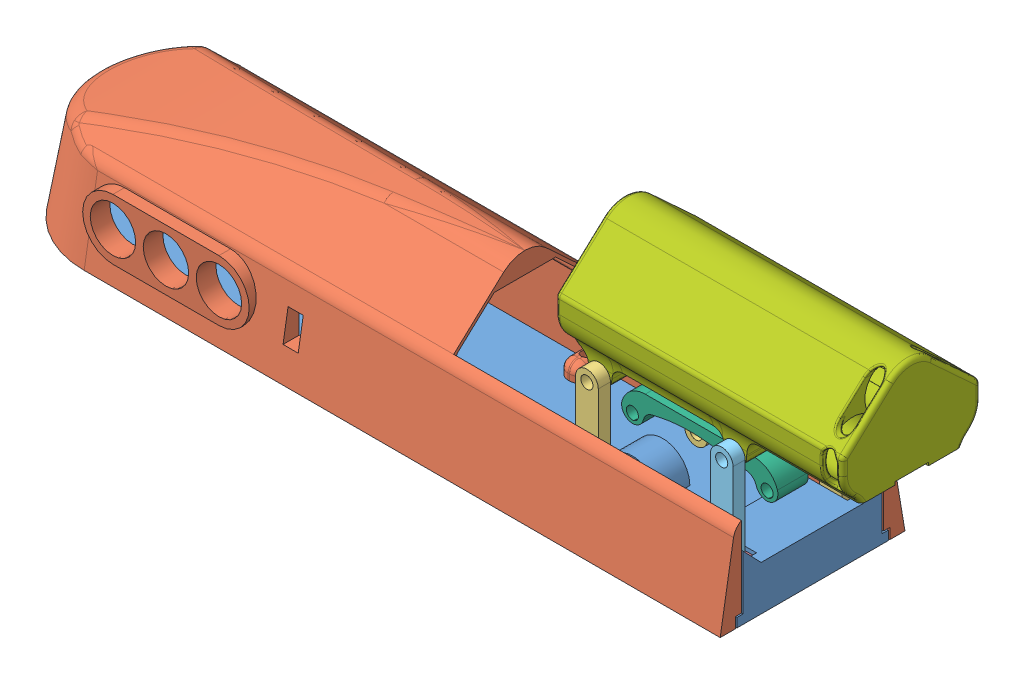
SolidWorks assembly Wrist Rockets Assembly, configuration Default. Lengths in mm.
Overall size (273.36 80.52 61).
9 component instances, 7 part files, 24 mates.
Components (placement in the parent):
- EC Base Plate-1: EC Base Plate [Default] at (1.705 116.0964 230.214) size (235 21 50)
- Casing-1: Casing [Default] at (211.705 119.0964 230.214) size (240.5 48 61)
- Lifter Bar-1: Lifter Bar [Default] at (157.205 156.5964 221.214) x (0 -1 0) z (-1 0 0) size (40 4 7.5)
- N20 Gear Motor-1: N20 Gear Motor [Default] at (207.705 119.0964 218.214) x (0 0 -1) z (1 0 0) size (31 10 12)
- Lifter Bar w Key-1: Lifter Bar w Key [Default] at (201.705 156.5964 221.214) x (0 -1 0) z (-1 0 0) size (40 4 7.5)
- Lifter Bar-2: Lifter Bar [Default] at (201.705 156.5964 185.214) x (0 -1 0) z (-1 0 0) size (40 4 7.5)
- Lifter Bar-3: Lifter Bar [Default] at (157.205 156.5964 185.214) x (0 -1 0) z (-1 0 0) size (40 4 7.5)
- Lifter Connector-1: Lifter Connector [Default] at (160.955 137.3464 205.214) size (51.62 10.5 10)
- Rocket Tube Housing-1: Rocket Tube Housing [Default] at (160.955 153.5964 210.714) size (95.11 43.02 45.5)
Mates (geometry in assembly coordinates):
- Coincident1: coincident aligned: plane of EC Base Plate-1 through (1.705 119.0964 230.214) normal (0 0 1); plane of Casing-1 through (211.705 119.0964 230.214) normal (0 0 1)
- Coincident2: coincident aligned: plane of EC Base Plate-1 through (1.705 119.0964 205.214) normal (0 1 0); plane of Casing-1 through (211.705 119.0964 230.214) normal (0 1 0)
- Coincident3: coincident aligned: plane of EC Base Plate-1 through (211.705 119.0964 230.214) normal (1 0 0); plane of Casing-1 through (211.705 119.0964 230.214) normal (1 0 0)
- Coincident4: coincident anti-aligned: plane of EC Base Plate-1 through (1.705 119.0964 205.214) normal (0 1 0); plane of N20 Gear Motor-1 through (207.705 119.0964 218.214) normal (0 -1 0)
- Distance1: distance = 4 mm aligned: plane of N20 Gear Motor-1 through (207.705 129.0964 218.214) normal (1 0 0); plane of EC Base Plate-1 through (211.705 119.0964 230.214) normal (1 0 0)
- Distance2: distance = 12 mm aligned: plane of N20 Gear Motor-1 through (207.705 129.0964 218.214) normal (0 0 1); plane of EC Base Plate-1 through (1.705 119.0964 230.214) normal (0 0 1)
- Concentric1: concentric aligned: cylinder of N20 Gear Motor-1 through (201.705 124.0964 228.214) axis (0 0 -1) radius 1.5; cylinder of Lifter Bar w Key-1 through (201.705 124.0964 225.214) axis (0 0 -1) radius 1.75
- Distance3: distance = 3 mm anti-aligned: plane of Lifter Bar w Key-1 through (201.705 156.5964 221.214) normal (0 0 -1); plane of N20 Gear Motor-1 through (207.705 129.0964 218.214) normal (0 0 1)
- LimitAngle1: limit planar angle = 1.570796 rad anti-aligned: plane of EC Base Plate-1 through (1.705 119.0964 205.214) normal (0 1 0); plane of Lifter Bar w Key-1 through (197.955 156.5964 225.214) normal (-1 0 0)
- Coincident9: coincident aligned: plane of Lifter Bar-1 through (157.205 156.5964 221.214) normal (0 0 -1); plane of Lifter Bar w Key-1 through (201.705 156.5964 221.214) normal (0 0 -1)
- Parallel2: parallel aligned: plane of Lifter Bar-1 through (160.955 156.5964 225.214) normal (1 0 0); plane of Lifter Bar w Key-1 through (205.455 156.5964 225.214) normal (1 0 0)
- Concentric2: concentric aligned: circle of EC Base Plate-1; circle of Lifter Bar-1
- Concentric3: concentric aligned: cylinder of Lifter Bar w Key-1 through (201.705 124.0964 225.214) axis (0 0 -1) radius 1.75; cylinder of Lifter Bar-2 through (201.705 124.0964 189.214) axis (0 0 -1) radius 2
- Distance4: distance = 3.5 mm anti-aligned: plane of Lifter Bar-2 through (201.705 156.5964 185.214) normal (0 0 -1); plane of Casing-1 through (1.705 146.0964 181.714) normal (0 0 1)
- Parallel3: parallel aligned: plane of Lifter Bar w Key-1 through (205.455 156.5964 225.214) normal (1 0 0); plane of Lifter Bar-2 through (205.455 156.5964 189.214) normal (1 0 0)
- Concentric4: concentric aligned: cylinder of EC Base Plate-1 through (157.205 124.0964 210.214) axis (0 0 -1) radius 2; cylinder of Lifter Bar-3 through (157.205 124.0964 189.214) axis (0 0 -1) radius 2
- Parallel4: parallel aligned: plane of Lifter Bar-2 through (205.455 156.5964 189.214) normal (1 0 0); plane of Lifter Bar-3 through (160.955 156.5964 189.214) normal (1 0 0)
- Distance5: distance = 3.5 mm anti-aligned: plane of Casing-1 through (1.705 146.0964 181.714) normal (0 0 1); plane of Lifter Bar-3 through (157.205 156.5964 185.214) normal (0 0 -1)
- Concentric8: concentric aligned: cylinder of Lifter Bar-2 through (201.705 140.3464 189.214) axis (0 0 -1) radius 2; cylinder of Lifter Connector-1 through (201.705 140.3464 210.214) axis (0 0 -1) radius 2
- Coincident10: coincident aligned: plane of EC Base Plate-1 through (157.205 119.0964 210.214) normal (0 0 1); plane of Lifter Connector-1 through (160.955 137.3464 210.214) normal (0 0 1)
- Concentric9: concentric aligned: cylinder of Lifter Bar-2 through (201.705 156.5964 189.214) axis (0 0 -1) radius 2; cylinder of Rocket Tube Housing-1 through (201.705 156.5964 220.714) axis (0 0 -1) radius 2
- Distance6: distance = 0.5 mm anti-aligned: plane of Rocket Tube Housing-1 through (160.955 153.5964 220.714) normal (0 0 1); plane of Lifter Bar w Key-1 through (201.705 156.5964 221.214) normal (0 0 -1)
- Parallel5: parallel anti-aligned: plane of Lifter Connector-1 through (153.455 147.8464 210.214) normal (0 1 0); plane of Rocket Tube Housing-1 through (237.455 164.5964 210.714) normal (0 -1 0)
- Parallel6: parallel aligned: plane of EC Base Plate-1 through (1.705 119.0964 205.214) normal (0 1 0); plane of Lifter Connector-1 through (153.455 147.8464 210.214) normal (0 1 0)
